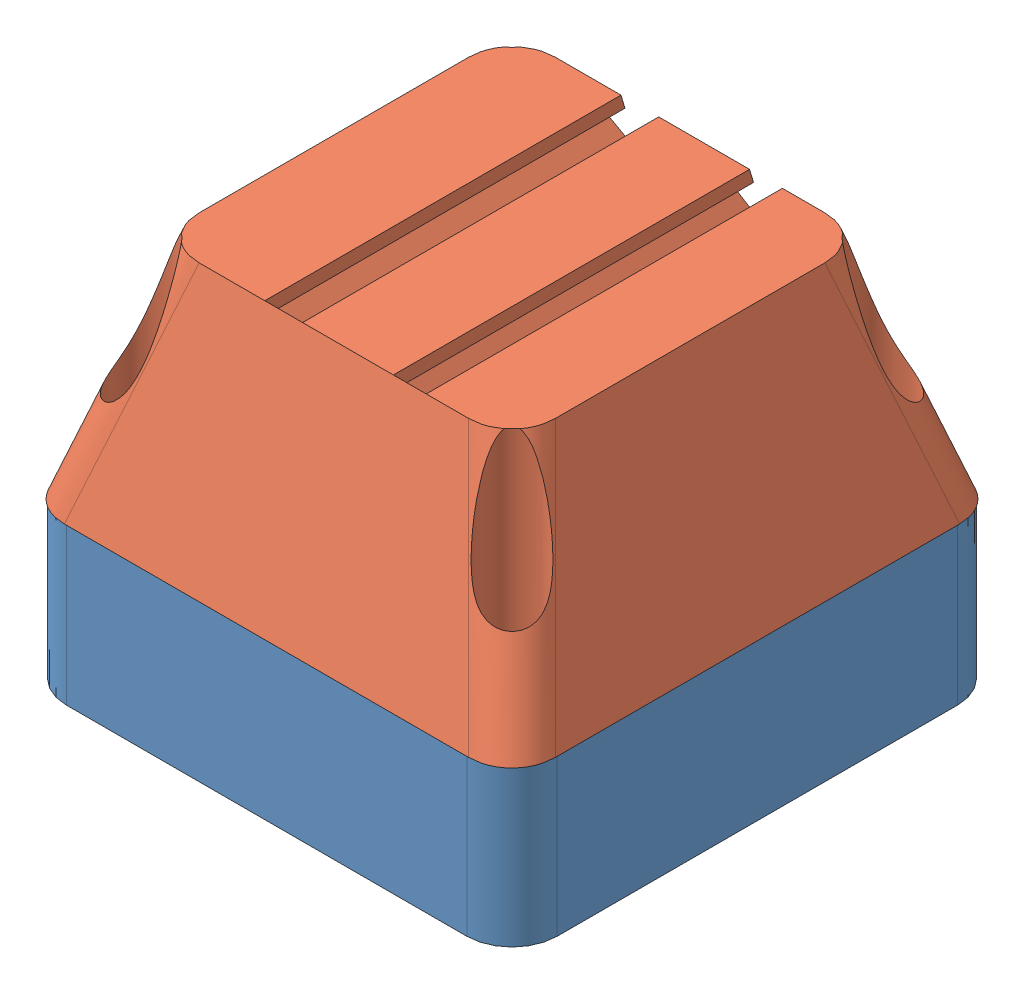
SolidWorks assembly Wheel Adapter, configuration Default. Lengths in mm.
Overall size (55.14 42.9 55.14).
2 component instances, 2 part files, 3 mates.
Components (placement in the parent):
- Base-1: Base [Default] at (25.5515 18.9886 46.3513) size (55.14 17.5 55.14)
- Transition-1: Transition [Default] at (25.5515 36.4886 46.3513) size (55.14 25.4 55.14)
Mates (geometry in assembly coordinates):
- Coincident1: coincident: plane of Base-1 through (25.5515 36.4886 46.3513) normal (0 1 0); plane of Transition-1 through (53.1215 36.4886 73.9213) normal (0 -1 0)
- Coincident2: coincident: line of Base-1 through (3.0615 36.4886 73.9213) axis (1 0 0); line of Transition-1 through (2.8498 36.4886 73.9213) axis (1 0 0)
- Coincident3: coincident: line of Base-1 through (53.1215 36.4886 68.8413) axis (0 0 -1); plane of Transition-1 through (50.8724 44.0351 46.3513) normal (0.958344 0.285617 0)
